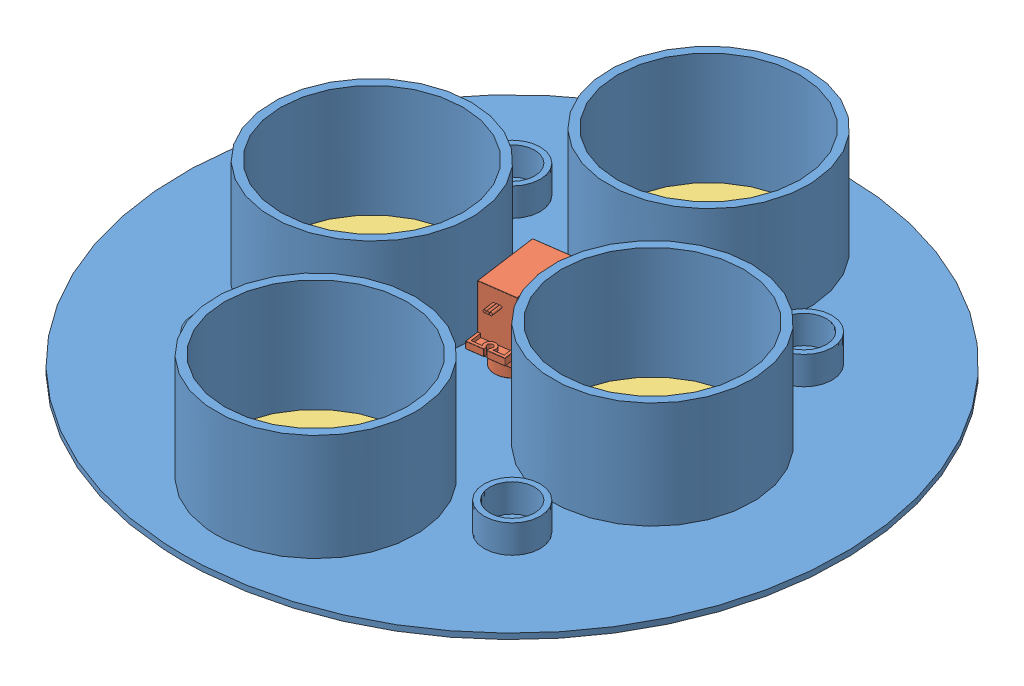
SolidWorks assembly Eksantirik tabalalı mekanizma, configuration Varsayılan. Lengths in mm.
Overall size (243.71 42 243.71).
3 component instances, 3 part files, 4 mates.
Components (placement in the parent):
- slotlar-1: slotlar [Varsayılan] at (-25.9978 -43.9839 225) size (235 40 235)
- TP SG90-1: TP SG90 [Varsayılan] at (-26.7192 -15.3839 219.7998) x (-0.990515 0 0.137404) z (0.137404 0 0.990515) size (12.64 29.82 33.01)
- delik plaka-1: delik plaka [Varsayılan] at (-25.9978 -45.9839 225) x (0.086932 0 0.996214) z (-0.996214 0 0.086932) size (225 2 225)
Mates (geometry in assembly coordinates):
- Çakışık1: coincident anti-aligned: plane of slotlar-1 through (-25.9978 -41.9839 225) normal (0 1 0); plane of TP SG90-1 through (-26.0923 -41.9839 224.319) normal (0 -1 0)
- Eş Merkezli1: concentric aligned: cylinder of slotlar-1 through (-25.9978 -41.9839 225) axis (0 -1 0) radius 5; cylinder of TP SG90-1 through (-25.9978 -37.8839 225) axis (0 -1 0) radius 6.25
- Eş Merkezli2: concentric aligned: cylinder of slotlar-1 through (-25.9978 -41.9839 225) axis (0 -1 0) radius 117.5; cylinder of delik plaka-1 through (-25.9978 -43.9839 225) axis (0 -1 0) radius 112.5
- Çakışık2: coincident anti-aligned: plane of slotlar-1 through (-25.9978 -43.9839 225) normal (0 -1 0); plane of delik plaka-1 through (-25.9978 -43.9839 225) normal (0 1 0)
